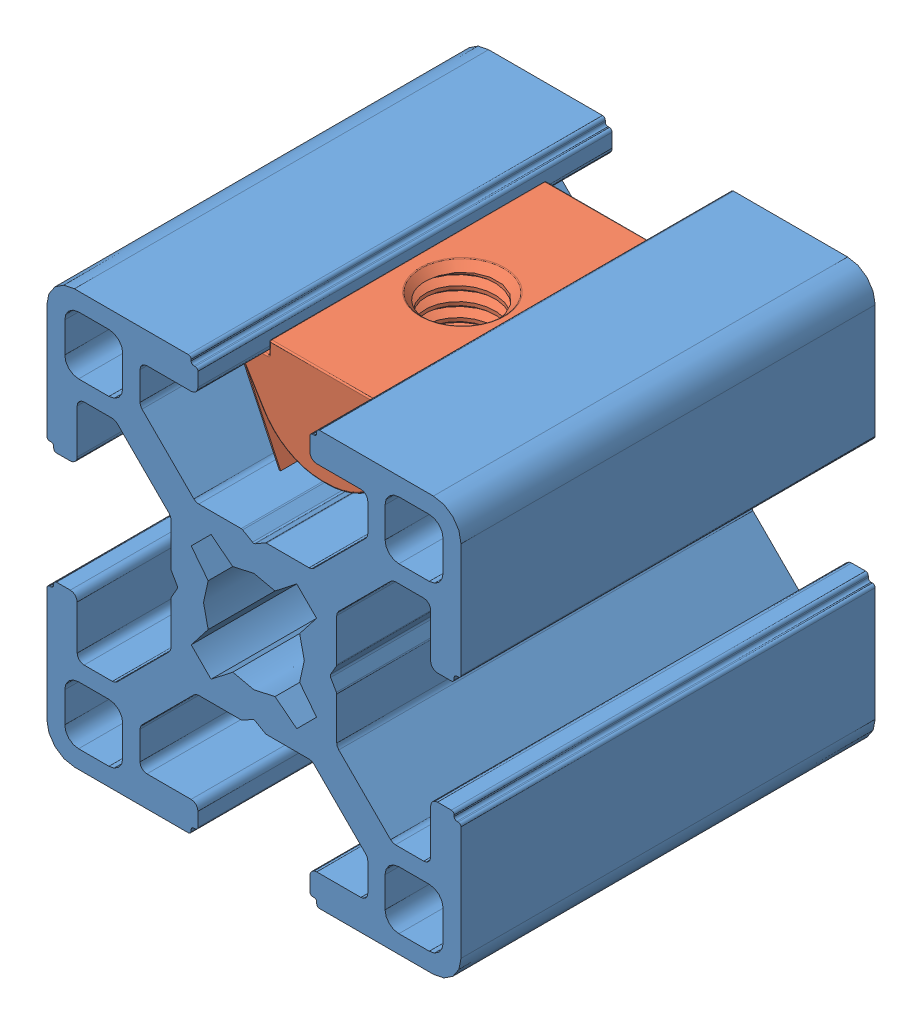
SolidWorks assembly СборкаТ-Сухарь 8 паз с лапкой, configuration По умолчанию. Lengths in mm.
Overall size (30 30 30).
2 component instances, 2 part files, 2 mates.
Components (placement in the parent):
- 30х30-1: 30х30 [По умолчанию] at origin size (30 30 30)
- Т-Сухарь паз 8 с лапкой-1: Т-Сухарь паз 8 с лапкой [По умолчанию] at (0.05 6.8 14.9506) size (12 13.76 20)
Mates (geometry in assembly coordinates):
- Совпадение1: coincident anti-aligned: plane of 30х30-1 through (0 12.8 30) normal (0 -1 0); plane of Т-Сухарь паз 8-1 through (-5.95 12.8 4.9506) normal (0 1 0)
- Расстояние1: distance = 0.1 mm anti-aligned: plane of 30х30-1 through (-4.05 0 30) normal (1 0 0); plane of Т-Сухарь паз 8 с лапкой-1 through (-3.95 12.8 4.9506) normal (-1 0 0)
